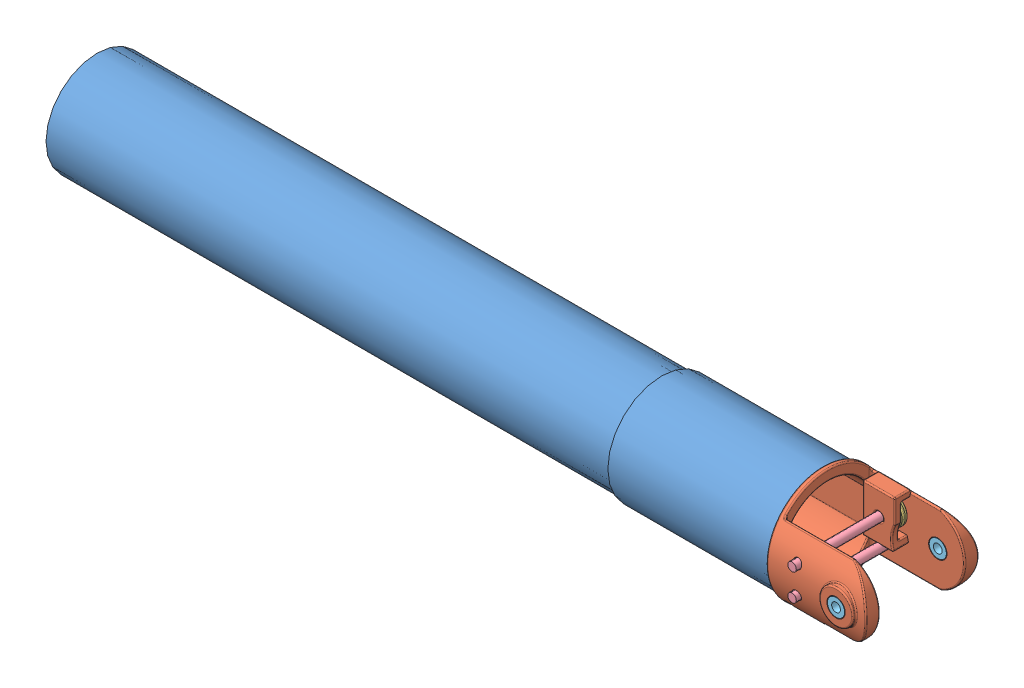
SolidWorks assembly Assem4^assembled_4dof_arm, configuration Default. Lengths in mm.
Overall size (307.31 42 44.45).
8 component instances, 5 part files, 12 mates.
Components (placement in the parent):
- carbon fiber tube 38mm 34mm-1: carbon fiber tube 38mm 34mm [Default] at (-297 0 0) size (270 40 40)
- j0 tube insert-1: j0 tube insert [Default] at (-54.1 0 0) x (1 0 0) z (0 0 -1) size (64.44 42 44.2)
- Pulley_configurable-1: Pulley_configurable [p3] at (-16.2481 5 -14.0971) x (0.158434 0.98737 0) z (-0.98737 0.158434 0) size (10.4 3 10.4)
- .125_2 inch shaft-1: .125_2 inch shaft [Default] at (-16.2481 5 -22.225) x (0.499926 -0.866068 0) z (0 0 1) size (3.17 3.17 44.45)
- 6377K490_ULTRA-LOW-FRICTION DRY-RUNNING SLEEVE BEARING-1: 6377K490_ULTRA-LOW-FRICTION DRY-RUNNING SLEEVE BEARING [6377K49] at (0 0 -18.925) x (-0.924225 -0.381849 0) z (0 0 -1) size (6.38 6.38 6.35)
- 6377K490_ULTRA-LOW-FRICTION DRY-RUNNING SLEEVE BEARING-2: 6377K490_ULTRA-LOW-FRICTION DRY-RUNNING SLEEVE BEARING [6377K49] at (0 0 18.925) x (-1 0 0) z (0 0 -1) size (6.38 6.38 6.35)
- Pulley_configurable-3: Pulley_configurable [p3] at (-16.2481 -5 14.0971) x (0.158434 -0.98737 0) z (-0.98737 -0.158434 0) size (10.4 3 10.4)
- .125_2 inch shaft-3: .125_2 inch shaft [Default] at (-16.2481 -5 22.225) x (0.499926 0.866068 0) z (0 0 -1) size (3.17 3.17 44.45)
Mates (geometry in assembly coordinates):
- Concentric48: concentric: cylinder of carbon fiber tube 38mm 34mm-1 through (-57 0 0) axis (-1 0 0) radius 17; cylinder of j0 tube insert-1 through (-54.1 0 0) axis (-1 0 0) radius 19.125
- Coincident59: coincident: plane of carbon fiber tube 38mm 34mm-1 through (-27 0 0) normal (1 0 0); plane of j0 tube insert-1 through (-27 -19.125 0) normal (-1 0 0)
- Concentric54: concentric: cylinder of j0 tube insert-1 through (-16.2481 5 21) axis (0 0 -1) radius 1.5875; cylinder of .125_2 inch shaft-1 through (-16.2481 5 22.225) axis (0 0 -1) radius 1.5875
- Concentric55: concentric: cylinder of j0 tube insert-1 through (0 0 21) axis (0 0 -1) radius 3.175; cylinder of 6377K490_ULTRA-LOW-FRICTION DRY-RUNNING SLEEVE BEARING-1 through (0 0 -22.1) axis (0 0 1) radius 3.1877
- Concentric56: concentric: cylinder of j0 tube insert-1 through (0 0 21) axis (0 0 -1) radius 3.175; cylinder of 6377K490_ULTRA-LOW-FRICTION DRY-RUNNING SLEEVE BEARING-2 through (0 0 15.75) axis (0 0 1) radius 3.1877
- Coincident63: coincident: plane of j0 tube insert-1 through (0 0 22.1) normal (0 0 1); plane of 6377K490_ULTRA-LOW-FRICTION DRY-RUNNING SLEEVE BEARING-2 through (0 0 22.1) normal (0 0 1)
- Coincident64: coincident: plane of j0 tube insert-1 through (0 0 -22.1) normal (0 0 -1); plane of 6377K490_ULTRA-LOW-FRICTION DRY-RUNNING SLEEVE BEARING-1 through (0 0 -22.1) normal (0 0 -1)
- Coincident61: coincident: circle of Pulley_configurable-1; cylinder of .125_2 inch shaft-1 through (-16.2481 5 22.225) axis (0 0 -1) radius 1.5875
- Width2: width: plane of .125_2 inch shaft-1 through (-16.2481 5 22.225) normal (0 0 1); plane of .125_2 inch shaft-1 through (-16.2481 5 -22.225) normal (0 0 -1); plane of j0 tube insert-1 through (10 0 -15.75) normal (0 0 1); plane of j0 tube insert-1 through (10 0 15.75) normal (0 0 -1)
- Coincident66: coincident: plane of j0 tube insert-1 through (-54.1 0 0) normal (0 0 -1); plane of assembly through (0 0 0) normal (0 0 1)
- Coincident67: coincident: plane of j0 tube insert-1 through (-54.1 0 0) normal (0 -1 0); plane of assembly through (0 0 0) normal (0 1 0)
- Coincident69: coincident: plane of 6377K490_ULTRA-LOW-FRICTION DRY-RUNNING SLEEVE BEARING-2 through (0 0 18.925) normal (-1 0 0); plane of assembly through (0 0 0) normal (1 0 0)
